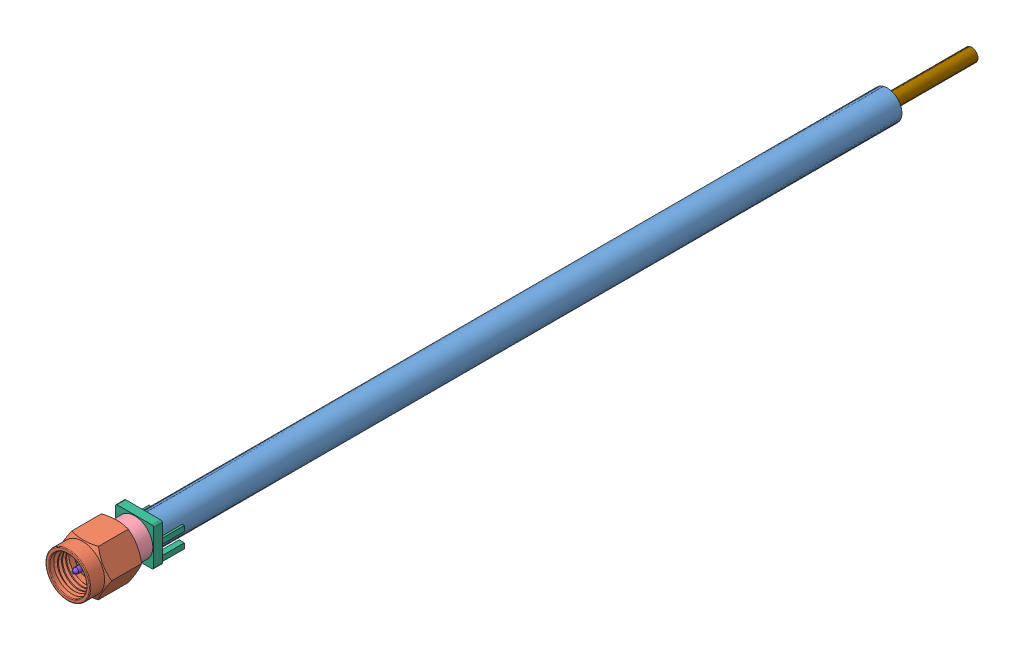
SolidWorks assembly Assem1, configuration Default. Lengths in mm.
Overall size (9.15 7.92 154.61).
10 component instances, 9 part files, 0 mates.
Components (placement in the parent):
- WIRE-1: WIRE [Default] at (57.9008 73.9805 -106.7669) size (5 5 127)
- SMA_male_edge_6.5x6.5.step-1: SMA_male_edge_6.5x6.5.step [Default] at (56.7337 75.3883 24.8124) size (9.15 7.92 16.93)
  - Nut.step-1: Nut.step [Default] at origin size (9.15 7.92 8.72)
  - Key.step-1: Key.step [Default] at origin size (7 7 0.9)
  - Sleeve.step-1: Sleeve.step [Default] at origin size (6.25 6.25 8)
  - Gasket.step-1: Gasket.step [Default] at origin size (6.25 6.25 0.65)
  - Base.step-1: Base.step [Default] at origin size (6.5 6.5 5.5)
  - Dielectric.step-1: Dielectric.step [Default] at origin size (4.25 4.25 9.5)
  - Pin.step-1: Pin.step [Default] at origin size (1.27 1.27 16.04)
- COAXLE-2: COAXLE [Default] at (57.5907 74.8146 -108.301) size (2.2 2.2 143)
